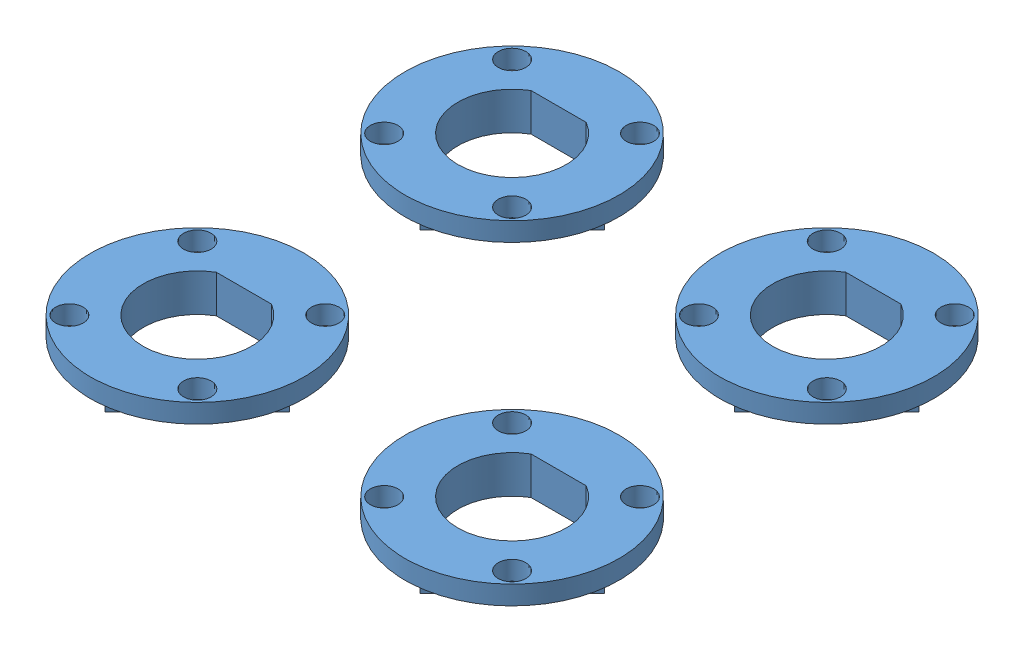
SolidWorks assembly 어셈블리1, configuration Default. Lengths in mm.
Overall size (42 3 42).
4 component instances, 1 part files, 6 mates.
Components (placement in the parent):
- pcb_motor_adp-1: pcb_motor_adp [Default] at (3.2175 7.1474 14.8519) size (17 3 17)
- pcb_motor_adp-2: pcb_motor_adp [Default] at (28.2175 7.1474 14.8519) size (17 3 17)
- pcb_motor_adp-3: pcb_motor_adp [Default] at (3.2175 7.1474 39.8519) size (17 3 17)
- pcb_motor_adp-4: pcb_motor_adp [Default] at (28.2175 7.1474 39.8519) size (17 3 17)
Mates (geometry in assembly coordinates):
- 일치1: coincident aligned: plane of pcb_motor_adp-1 through (3.2175 10.1474 14.8519) normal (0 1 0); plane of pcb_motor_adp-2 through (28.2555 10.1474 14.4854) normal (0 1 0)
- 일치2: coincident aligned: plane of pcb_motor_adp-1 through (3.2175 10.1474 14.8519) normal (0 1 0); plane of pcb_motor_adp-3 through (2.8294 10.1474 39.5872) normal (0 1 0)
- 일치3: coincident aligned: plane of pcb_motor_adp-1 through (3.2175 10.1474 14.8519) normal (0 1 0); plane of pcb_motor_adp-4 through (29.6176 10.1474 40.1709) normal (0 1 0)
- 동심1: concentric: cylinder of pcb_motor_adp-2 through (28.2175 7.1474 14.8519) axis (0 1 0) radius 4.3; point of assembly
- 동심2: concentric: cylinder of pcb_motor_adp-4 through (28.2175 7.1474 39.8519) axis (0 1 0) radius 4.3; point of assembly
- 동심3: concentric: cylinder of pcb_motor_adp-3 through (3.2175 7.1474 39.8519) axis (0 1 0) radius 4.3; point of assembly
